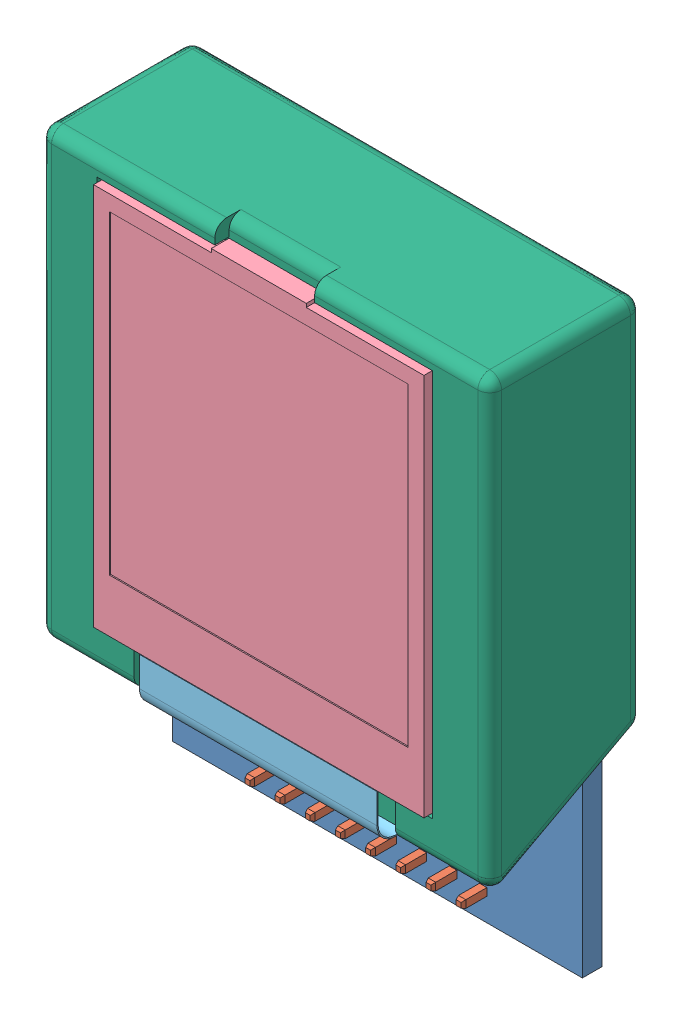
SolidWorks assembly Screen Assembly v2, configuration Default. Lengths in mm.
Overall size (37.96 50.27 18.7).
6 component instances, 6 part files, 17 mates.
Components (placement in the parent):
- Screen v2 PCB-1: Screen v2 PCB [34.5mm width] at origin size (34.5 47.27 1.65)
- Straight Header - 1x8-1: Straight Header - 1x8 [Default] at (40.64 -21.385 0) size (20.12 2.54 10.71)
- Led Panel-1: Led Panel [Default] at (0 7.815 4.65) size (35.48 36.23 5.6)
- TFT panel-1: TFT panel [Default] at (0 9.085 10.15) size (27.82 32.57 1.5)
- Part3^Screen Assembly v2-1: Part3^Screen Assembly v2 [Default] x (0 0 -1) z (1 0 0) size (10.1 5.32 20) (virtual)
- Screen Bracket v2-1: Screen Bracket v2 [Default] at origin size (37.9 38.71 12.85)
Mates (geometry in assembly coordinates):
- Coincident2: coincident: plane of assembly through (0 0 0) normal (1 0 0); plane of Led Panel-1 through (0 7.815 4.65) normal (1 0 0); plane of assembly
- Distance1: distance = 0.2 mm: plane of Led Panel-1 through (0 7.815 1.85) normal (0 0 -1); plane of ? through (0 0 1.65) normal (0 0 1)
- Coincident5: coincident: plane of assembly through (0 0 0) normal (1 0 0); plane of TFT panel-1 through (0 9.085 10.15) normal (1 0 0); plane of assembly
- Distance2: distance = 8.5 mm: plane of ? through (0 0 1.65) normal (0 0 1); plane of TFT panel-1 through (0 9.085 10.15) normal (0 0 -1)
- Coincident7: coincident: plane of ? through (17.25 23.635 1.65) normal (0 1 0); plane of TFT panel-1 through (4 23.635 11.65) normal (0 1 0)
- Width2: width: plane of assembly; plane of assembly; plane of assembly; plane of assembly; plane of TFT panel-1 through (-12.585 -4.165 11.65) normal (0 1 0); plane of TFT panel-1 through (-12.585 22.335 11.65) normal (0 -1 0); plane of Led Panel-1 through (12.48 20.665 2.15) normal (0 1 0); plane of Led Panel-1 through (12.48 -2.495 2.15) normal (0 -1 0)
- InPlace1: in place: plane of Part3^Screen Assembly v2-1 through (0 0 0) normal (1 0 0); moOrthogonalPlaneRef_w of Part3^Screen Assembly v2-1 through (0 0 0) normal (0 1 0); plane of Part3^Screen Assembly v2-1 through (0 0 0) normal (0 0 -1); unknown of Part3^Screen Assembly v2-1
- Coincident8: coincident: plane of assembly; plane of Part3^Screen Assembly v2-1; plane of assembly
- Coincident9: coincident: plane of assembly; plane of Part3^Screen Assembly v2-1 through (0 0 0) normal (0 1 0); moOrthogonalPlaneRef_w of assembly
- Coincident10: coincident: plane of assembly; plane of Part3^Screen Assembly v2-1 through (0 0 0) normal (0 0 -1); moOrthogonalPlaneRef_w of assembly
- InPlace2: in place: plane of ? through (0 0 0) normal (0 0 1); plane of ? through (0 0 0) normal (0 1 0); plane of ? through (0 0 0) normal (1 0 0); unknown of ?
- Coincident11: coincident: plane of assembly; plane of Screen Bracket v2-1; plane of assembly
- Coincident12: coincident: plane of ? through (0 0 0) normal (0 1 0)
- Coincident13: coincident: plane of ? through (0 0 0) normal (1 0 0)
- Width5: width: plane of ? through (-9.215 -21.06 3.05) normal (1 0 0); plane of ? through (9.215 -21.06 3.05) normal (-1 0 0); plane of Straight Header - 1x8-1 through (9.2012 -21.7025 3.714) normal (1 0 0); plane of Straight Header - 1x8-1 through (-9.2012 -21.0675 3.714) normal (-1 0 0)
- Coincident12: coincident: plane of ? through (0 0 0) normal (0 0 -1); plane of Straight Header - 1x8-1 through (40.64 -21.385 0) normal (0 0 1)
- Width6: width: plane of Straight Header - 1x8-1 through (-8.5789 -21.0675 3.714) normal (0 1 0); plane of Straight Header - 1x8-1 through (-9.2012 -21.7025 3.714) normal (0 -1 0); plane of ? through (-9.215 -21.71 3.05) normal (0 1 0); plane of ? through (-9.215 -21.06 3.05) normal (0 -1 0)
